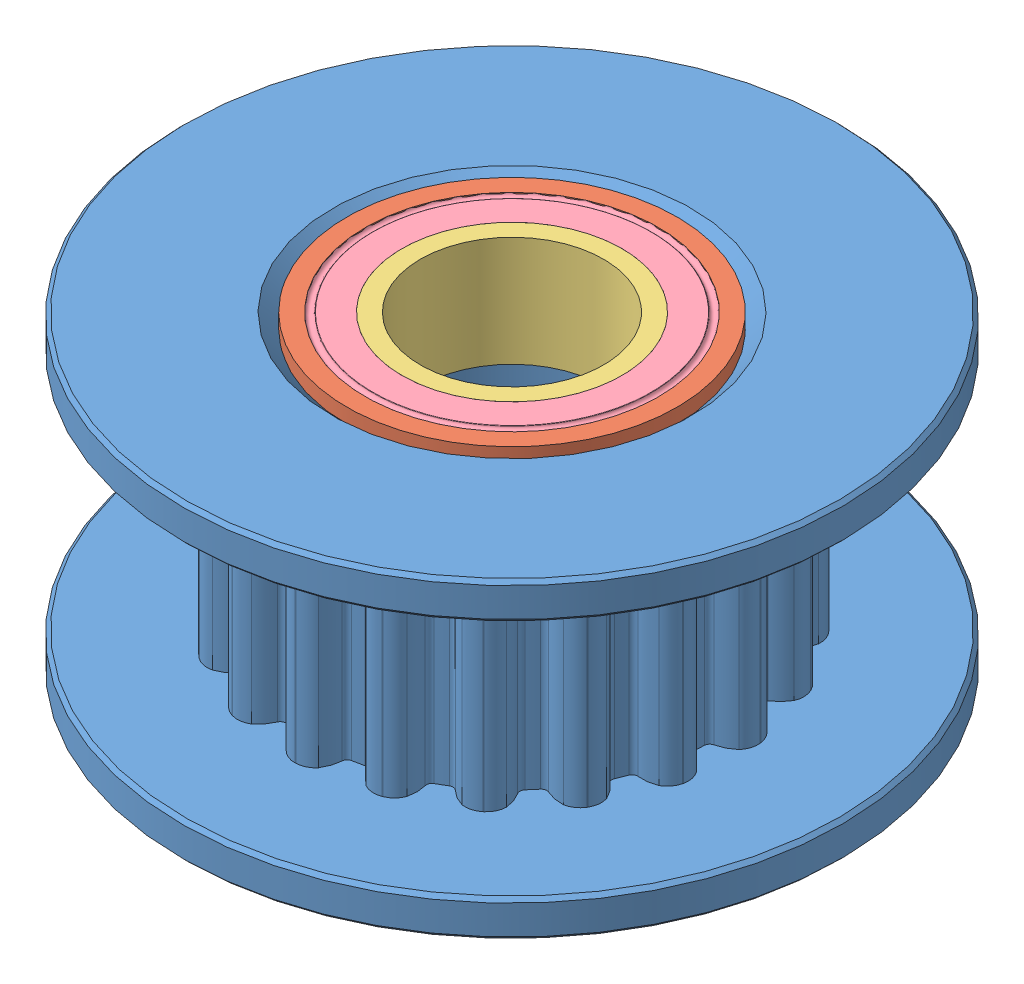
SolidWorks assembly 5 mm GT2 Timing Idler Pulley, Configurable, configuration 20T W6 B5 With T. Lengths in mm.
Overall size (25.08 8.5 25.08).
35 component instances, 5 part files, 5 mates.
Components (placement in the parent):
- Body, GT2 Timing Idler Pulley, Configurable-1: Body, GT2 Timing Idler Pulley, Configurable [20T W6 B5 With T] x (-0.574695 0 -0.818368) z (0.818368 0 -0.574695) size (18 8.5 18)
- Bearing Subassy, GT2 Timing Idler Pulley, Configurable-1: Bearing Subassy, GT2 Timing Idler Pulley, Configurable [5 mm Bore] at (0 2.75 0) x (0.574695 0 0.818368) z (-0.818368 0 0.574695) size (9 3 9)
  - Bearing Outer Ring, GT2 Timing Idler Pulley, Configurable-1: Bearing Outer Ring, GT2 Timing Idler Pulley, Configurable [5 mm Bore] at origin size (9 3 9)
  - Bearing Inner Ring, GT2 Timing Idler Pulley, Configurable-1: Bearing Inner Ring, GT2 Timing Idler Pulley, Configurable [5 mm Bore] x (0.926062 0 -0.377371) z (0.377371 0 0.926062) size (6 3 6)
  - Bearing Seal, GT2 Timing Idler Pulley, Configurable-1: Bearing Seal, GT2 Timing Idler Pulley, Configurable [5 mm Bore] at (0 1.25 0) size (8 0.5 8)
  - Bearing Seal, GT2 Timing Idler Pulley, Configurable-2: Bearing Seal, GT2 Timing Idler Pulley, Configurable [5 mm Bore] at (0 -1.25 0) x (1 0 0) z (0 0 -1) size (8 0.5 8)
  - Bearing Ball, GT2 Timing Idler Pulley, Configurable-1: Bearing Ball, GT2 Timing Idler Pulley, Configurable [1.4 mm] at (-2.4745 0 -2.4753) x (-0.715461 0 0.698652) z (-0.698652 0 -0.715461) size (1.4 1.4 1.4)
  - Bearing Ball, GT2 Timing Idler Pulley, Configurable-2: Bearing Ball, GT2 Timing Idler Pulley, Configurable [1.4 mm] at (-0.9053 0 -3.3809) x (-0.968934 0 0.24732) z (-0.24732 0 -0.968934) size (1.4 1.4 1.4)
  - Bearing Ball, GT2 Timing Idler Pulley, Configurable-3: Bearing Ball, GT2 Timing Idler Pulley, Configurable [1.4 mm] at (0.9064 0 -3.3806) x (-0.962781 0 -0.270282) z (0.270282 0 -0.962781) size (1.4 1.4 1.4)
  - Bearing Ball, GT2 Timing Idler Pulley, Configurable-4: Bearing Ball, GT2 Timing Idler Pulley, Configurable [1.4 mm] at (2.4753 0 -2.4745) x (-0.698652 0 -0.715461) z (0.715461 0 -0.698652) size (1.4 1.4 1.4)
  - Bearing Ball, GT2 Timing Idler Pulley, Configurable-5: Bearing Ball, GT2 Timing Idler Pulley, Configurable [1.4 mm] at (3.3809 0 -0.9053) x (-0.24732 0 -0.968934) z (0.968934 0 -0.24732) size (1.4 1.4 1.4)
  - Bearing Ball, GT2 Timing Idler Pulley, Configurable-6: Bearing Ball, GT2 Timing Idler Pulley, Configurable [1.4 mm] at (3.3806 0 0.9064) x (0.270282 0 -0.962781) z (0.962781 0 0.270282) size (1.4 1.4 1.4)
  - Bearing Ball, GT2 Timing Idler Pulley, Configurable-7: Bearing Ball, GT2 Timing Idler Pulley, Configurable [1.4 mm] at (2.4745 0 2.4753) x (0.715461 0 -0.698652) z (0.698652 0 0.715461) size (1.4 1.4 1.4)
  - Bearing Ball, GT2 Timing Idler Pulley, Configurable-8: Bearing Ball, GT2 Timing Idler Pulley, Configurable [1.4 mm] at (0.9053 0 3.3809) x (0.968934 0 -0.24732) z (0.24732 0 0.968934) size (1.4 1.4 1.4)
  - Bearing Ball, GT2 Timing Idler Pulley, Configurable-9: Bearing Ball, GT2 Timing Idler Pulley, Configurable [1.4 mm] at (-0.9064 0 3.3806) x (0.962781 0 0.270282) z (-0.270282 0 0.962781) size (1.4 1.4 1.4)
  - Bearing Ball, GT2 Timing Idler Pulley, Configurable-10: Bearing Ball, GT2 Timing Idler Pulley, Configurable [1.4 mm] at (-2.4753 0 2.4745) x (0.698652 0 0.715461) z (-0.715461 0 0.698652) size (1.4 1.4 1.4)
  - Bearing Ball, GT2 Timing Idler Pulley, Configurable-11: Bearing Ball, GT2 Timing Idler Pulley, Configurable [1.4 mm] at (-3.3809 0 0.9053) x (0.24732 0 0.968934) z (-0.968934 0 0.24732) size (1.4 1.4 1.4)
  - Bearing Ball, GT2 Timing Idler Pulley, Configurable-12: Bearing Ball, GT2 Timing Idler Pulley, Configurable [1.4 mm] at (-3.3806 0 -0.9064) x (-0.270282 0 0.962781) z (-0.962781 0 -0.270282) size (1.4 1.4 1.4)
- Bearing Subassy, GT2 Timing Idler Pulley, Configurable-2: Bearing Subassy, GT2 Timing Idler Pulley, Configurable [5 mm Bore] at (0 -2.75 0) x (0.574695 0 0.818368) z (0.818368 0 -0.574695) size (9 3 9)
  - Bearing Outer Ring, GT2 Timing Idler Pulley, Configurable-1: Bearing Outer Ring, GT2 Timing Idler Pulley, Configurable [5 mm Bore] at origin size (9 3 9)
  - Bearing Inner Ring, GT2 Timing Idler Pulley, Configurable-1: Bearing Inner Ring, GT2 Timing Idler Pulley, Configurable [5 mm Bore] x (0.926062 0 -0.377371) z (0.377371 0 0.926062) size (6 3 6)
  - Bearing Seal, GT2 Timing Idler Pulley, Configurable-1: Bearing Seal, GT2 Timing Idler Pulley, Configurable [5 mm Bore] at (0 1.25 0) size (8 0.5 8)
  - Bearing Seal, GT2 Timing Idler Pulley, Configurable-2: Bearing Seal, GT2 Timing Idler Pulley, Configurable [5 mm Bore] at (0 -1.25 0) x (1 0 0) z (0 0 -1) size (8 0.5 8)
  - Bearing Ball, GT2 Timing Idler Pulley, Configurable-1: Bearing Ball, GT2 Timing Idler Pulley, Configurable [1.4 mm] at (-2.4745 0 -2.4753) x (-0.715461 0 0.698652) z (-0.698652 0 -0.715461) size (1.4 1.4 1.4)
  - Bearing Ball, GT2 Timing Idler Pulley, Configurable-2: Bearing Ball, GT2 Timing Idler Pulley, Configurable [1.4 mm] at (-0.9053 0 -3.3809) x (-0.968934 0 0.24732) z (-0.24732 0 -0.968934) size (1.4 1.4 1.4)
  - Bearing Ball, GT2 Timing Idler Pulley, Configurable-3: Bearing Ball, GT2 Timing Idler Pulley, Configurable [1.4 mm] at (0.9064 0 -3.3806) x (-0.962781 0 -0.270282) z (0.270282 0 -0.962781) size (1.4 1.4 1.4)
  - Bearing Ball, GT2 Timing Idler Pulley, Configurable-4: Bearing Ball, GT2 Timing Idler Pulley, Configurable [1.4 mm] at (2.4753 0 -2.4745) x (-0.698652 0 -0.715461) z (0.715461 0 -0.698652) size (1.4 1.4 1.4)
  - Bearing Ball, GT2 Timing Idler Pulley, Configurable-5: Bearing Ball, GT2 Timing Idler Pulley, Configurable [1.4 mm] at (3.3809 0 -0.9053) x (-0.24732 0 -0.968934) z (0.968934 0 -0.24732) size (1.4 1.4 1.4)
  - Bearing Ball, GT2 Timing Idler Pulley, Configurable-6: Bearing Ball, GT2 Timing Idler Pulley, Configurable [1.4 mm] at (3.3806 0 0.9064) x (0.270282 0 -0.962781) z (0.962781 0 0.270282) size (1.4 1.4 1.4)
  - Bearing Ball, GT2 Timing Idler Pulley, Configurable-7: Bearing Ball, GT2 Timing Idler Pulley, Configurable [1.4 mm] at (2.4745 0 2.4753) x (0.715461 0 -0.698652) z (0.698652 0 0.715461) size (1.4 1.4 1.4)
  - Bearing Ball, GT2 Timing Idler Pulley, Configurable-8: Bearing Ball, GT2 Timing Idler Pulley, Configurable [1.4 mm] at (0.9053 0 3.3809) x (0.968934 0 -0.24732) z (0.24732 0 0.968934) size (1.4 1.4 1.4)
  - Bearing Ball, GT2 Timing Idler Pulley, Configurable-9: Bearing Ball, GT2 Timing Idler Pulley, Configurable [1.4 mm] at (-0.9064 0 3.3806) x (0.962781 0 0.270282) z (-0.270282 0 0.962781) size (1.4 1.4 1.4)
  - Bearing Ball, GT2 Timing Idler Pulley, Configurable-10: Bearing Ball, GT2 Timing Idler Pulley, Configurable [1.4 mm] at (-2.4753 0 2.4745) x (0.698652 0 0.715461) z (-0.715461 0 0.698652) size (1.4 1.4 1.4)
  - Bearing Ball, GT2 Timing Idler Pulley, Configurable-11: Bearing Ball, GT2 Timing Idler Pulley, Configurable [1.4 mm] at (-3.3809 0 0.9053) x (0.24732 0 0.968934) z (-0.968934 0 0.24732) size (1.4 1.4 1.4)
  - Bearing Ball, GT2 Timing Idler Pulley, Configurable-12: Bearing Ball, GT2 Timing Idler Pulley, Configurable [1.4 mm] at (-3.3806 0 -0.9064) x (-0.270282 0 0.962781) z (-0.962781 0 -0.270282) size (1.4 1.4 1.4)
Mates (geometry in assembly coordinates):
- Coincident2: coincident: point of Body, GT2 Timing Idler Pulley, Configurable-1
- Coincident3: coincident aligned: plane of Body, GT2 Timing Idler Pulley, Configurable-1 through (0 0 0) normal (0 1 0)
- Concentric1: concentric anti-aligned: cylinder of Body, GT2 Timing Idler Pulley, Configurable-1 through (0 4.25 0) axis (0 1 0) radius 4.5; cylinder of Bearing Subassy, GT2 Timing Idler Pulley, Configurable-1/Bearing Outer Ring, GT2 Timing Idler Pulley, Configurable-1 through (0 4.25 0) axis (0 -1 0) radius 4.5
- Coincident4: coincident anti-aligned: plane of Body, GT2 Timing Idler Pulley, Configurable-1 through (-2.5861 1.25 -3.6827) normal (0 1 0); plane of Bearing Subassy, GT2 Timing Idler Pulley, Configurable-1/Bearing Outer Ring, GT2 Timing Idler Pulley, Configurable-1 through (0 1.25 0) normal (0 -1 0)
- Coincident6: coincident anti-aligned: plane of Body, GT2 Timing Idler Pulley, Configurable-1 through (0 0 0) normal (-0.574695 0 -0.818368); plane of Bearing Subassy, GT2 Timing Idler Pulley, Configurable-1/Bearing Outer Ring, GT2 Timing Idler Pulley, Configurable-1 through (0 2.75 0) normal (0.574695 0 0.818368)
